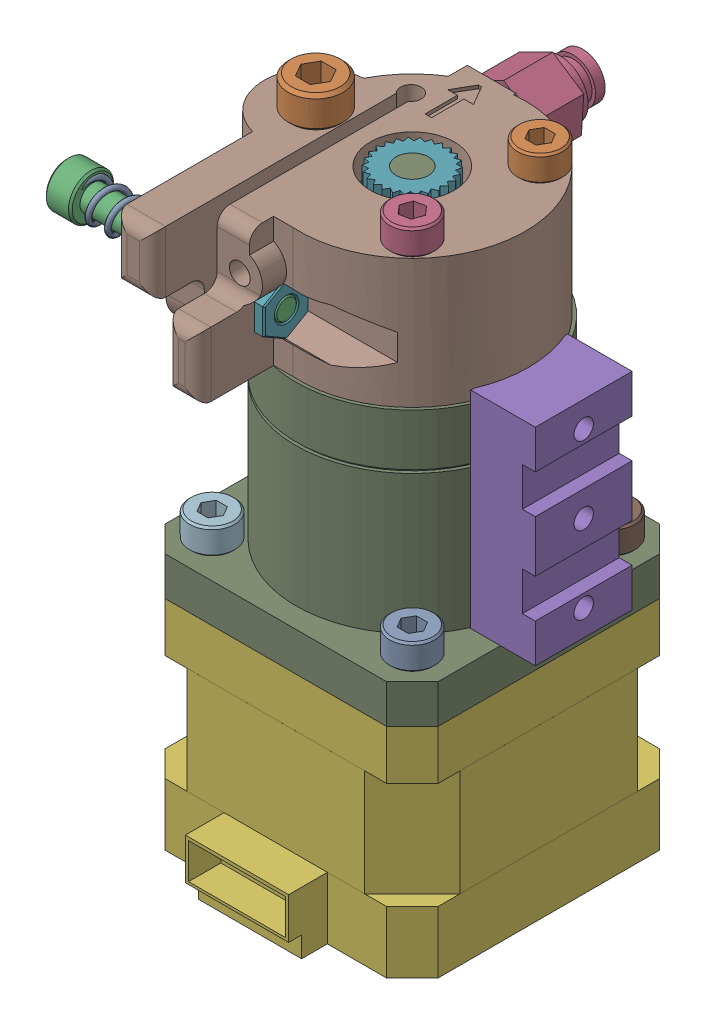
SolidWorks assembly stepper motor with Planetary gearbox, configuration Default. Lengths in mm.
Overall size (63.06 94.75 61.1).
19 component instances, 15 part files, 0 mates.
Components (placement in the parent):
- spring012-1: spring012 [Default] at (-18.0118 60.75 16.9595) x (0 -0.866025 0.5) z (0 -0.5 -0.866025) size (5.97 17.35 5.97)
- m4x25 socket screw-1: m4x25 socket screw [Default] at (9.9 47.75 -9.9) size (7 29 7)
- m4x30 socket screw-1: m4x30 socket screw [Default] at (-2.5118 60.75 16.9595) x (0 -0.192085 0.981378) z (0 -0.981378 -0.192085) size (7 34 7)
- KQB2H04-M5_2_14a-1: KQB2H04-M5_2_14a [Default] at (-5.5118 66.25 -14.7945) x (-0.997907 0.064662 0) z (-0.064662 -0.997907 0) size (10 17.1 11.55)
- Gasket id4.2-1: Gasket id4.2 [Default] at (-17.0118 60.75 16.9595) x (0 -0.866025 0.5) z (0 -0.5 -0.866025) size (8 1 8)
- MP1872-Stepper_Motor_NEMA17-1: MP1872-Stepper_Motor_NEMA17 [Default] at origin size (42.3 53.75 48.3)
- m4 nut-1: m4 nut [Default] at (-2.5118 60.75 16.9595) x (0 -0.5 0.866025) z (0 -0.866025 -0.5) size (8.08 3 7)
- extruder sw-1: extruder sw [Default] at (0 52.75 0) x (-1 0 0) z (0 -1 0) size (40.5 47 20)
- Planetary gearbox-1: Planetary gearbox [Default] at (0 16.75 0) x (-1 0 0) z (0 1 0) size (42.3 42.3 56)
- m4x10 socket screw-1: m4x10 socket screw [Default] at (-15.5 12.75 -15.5) size (7 14 7)
- m4x10 socket screw-2: m4x10 socket screw [Default] at (15.5 12.75 -15.5) size (7 14 7)
- m4x10 socket screw-3: m4x10 socket screw [Default] at (-15.5 12.75 15.5) size (7 14 7)
- m4x10 socket screw-4: m4x10 socket screw [Default] at (15.5 12.75 15.5) size (7 14 7)
- M5x20 socket screw-1: M5x20 socket screw [Default] at (-14.9972 52.75 -0.0367) size (8.5 25 8.5)
- 625zz ball bearing-1: 625zz ball bearing [Default] at (-14.9972 63.25 -0.0367) x (0.614342 0 0.78904) z (-0.78904 0 0.614342) size (16 5 16)
- m4x25 socket screw-2: m4x25 socket screw [Default] at (9.9 47.75 9.9) x (0.326979 0 -0.945032) z (0.945032 0 0.326979) size (7 29 7)
- frame_extruder sw-1: frame_extruder sw [Default] at (26.5474 22.75 0) x (0 0 1) z (0 -1 0) size (15 10 32)
- m5 nut-1: m5 nut [Default] at (-14.9972 54.75 -0.0367) x (0.963483 0 -0.267769) z (0.267769 0 0.963483) size (8 4 9.24)
- Spur Gear-1: Spur Gear [Default] at (0 61.75 0) x (0.734828 0 -0.678253) z (0.678253 0 0.734828) size (11 11 10.92)
